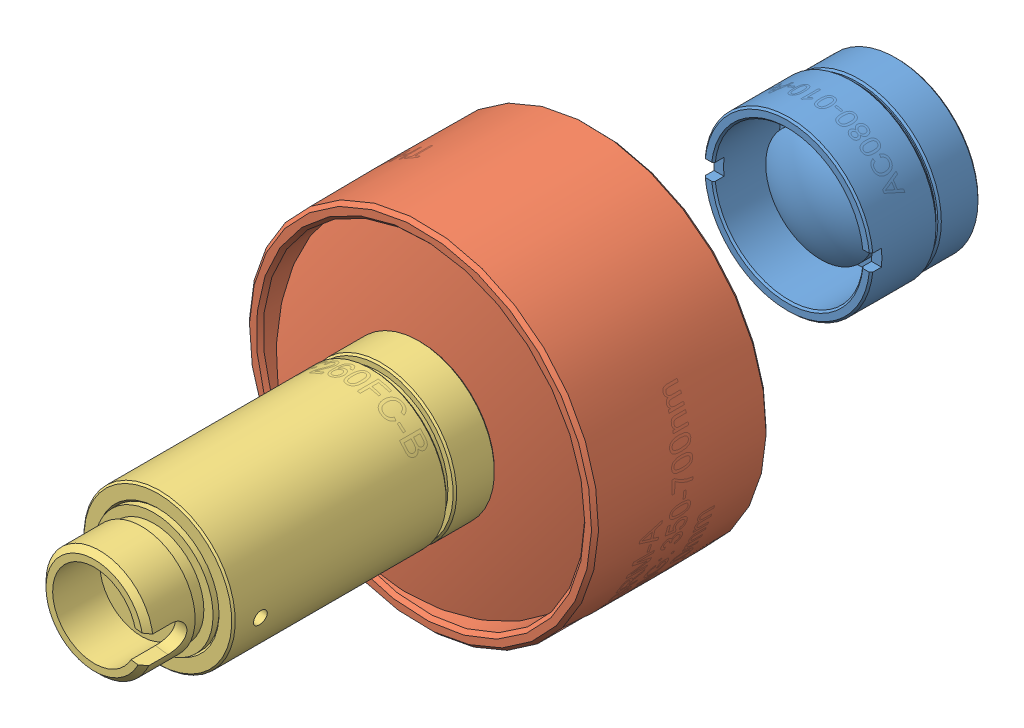
SolidWorks assembly LightSheetTZV, configuration Default. Lengths in mm.
Overall size (35.61 35.61 58.4).
3 component instances, 3 part files, 4 mates.
Components (placement in the parent):
- AC080-010-A-ML-Solidworks-1: AC080-010-A-ML-Solidworks [Default] at (0.6396 6.3917 11.4662) size (12.24 12.24 8)
- LJ1703RM-A-Solidworks(1)-1: LJ1703RM-A-Solidworks(1) [Default] at (0.6396 6.3917 35.7951) x (0.608553 0.793513 0) z (0.793513 -0.608553 0) size (25.4 12.7 25.4)
- F260FC-B-Solidworks-2: F260FC-B-Solidworks [Default] at (0.6396 6.3917 51.6955) x (-0.990825 0.135155 0) z (0 0 -1) size (11 11 23.72)
Mates (geometry in assembly coordinates):
- Concentric2: concentric: cylinder of AC080-010-A-ML-Solidworks-1 through (0.6396 6.3917 15.4667) axis (0 0 1) radius 6.1201; cylinder of LJ1703RM-A-Solidworks(1)-1 through (0.6396 6.3917 42.1451) axis (0 0 1) radius 12.7
- Coincident1: coincident: plane of LJ1703RM-A-Solidworks(1)-1 through (-7.0891 -3.6859 29.4451) normal (0 0 -1); point of assembly
- Concentric3: concentric: cylinder of LJ1703RM-A-Solidworks(1)-1 through (0.6396 6.3917 42.1451) axis (0 0 1) radius 12.7; cylinder of F260FC-B-Solidworks-2 through (0.6396 6.3917 42.1451) axis (0 0 -1) radius 5.4991
- Coincident2: coincident: plane of LJ1703RM-A-Solidworks(1)-1 through (-6.4785 -2.8898 42.1451) normal (0 0 1); plane of F260FC-B-Solidworks-2 through (1.0802 9.6219 42.1451) normal (0 0 -1)
